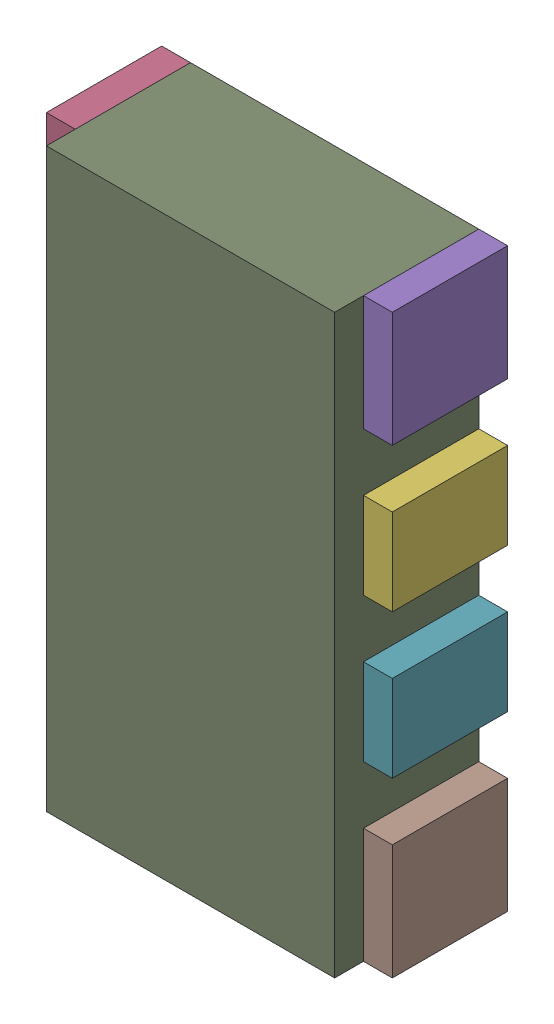
SolidWorks assembly RN9, configuration Default. Lengths in mm.
Overall size (1.2 2 0.5).
18 component instances, 3 part files, 0 mates.
Components (placement in the parent):
- 791587232-1: 791587232 [Default] at (130.6 47.1 0) size (0.1 0.4 0.4)
  - Extruded_10-1: Extruded_10 [Default] at origin size (0.1 0.4 0.4)
- 836750576-1: 836750576 [Default] at (130.6 47.65 0) size (0.1 0.3 0.4)
  - Extruded_14-1: Extruded_14 [Default] at origin size (0.1 0.3 0.4)
- 836750576-2: 836750576 [Default] at (130.6 48.15 0) size (0.1 0.3 0.4)
  - Extruded_14-1: Extruded_14 [Default] at origin size (0.1 0.3 0.4)
- 791587232-2: 791587232 [Default] at (130.6 48.7 0) size (0.1 0.4 0.4)
  - Extruded_10-1: Extruded_10 [Default] at origin size (0.1 0.4 0.4)
- 791587232-3: 791587232 [Default] at (131.7 48.7 0) size (0.1 0.4 0.4)
  - Extruded_10-1: Extruded_10 [Default] at origin size (0.1 0.4 0.4)
- 836750576-3: 836750576 [Default] at (131.7 48.15 0) size (0.1 0.3 0.4)
  - Extruded_14-1: Extruded_14 [Default] at origin size (0.1 0.3 0.4)
- 836750576-4: 836750576 [Default] at (131.7 47.65 0) size (0.1 0.3 0.4)
  - Extruded_14-1: Extruded_14 [Default] at origin size (0.1 0.3 0.4)
- 791587232-4: 791587232 [Default] at (131.7 47.1 0) size (0.1 0.4 0.4)
  - Extruded_10-1: Extruded_10 [Default] at origin size (0.1 0.4 0.4)
- 836750320-1: 836750320 [Default] at (131.15 47.9 0) size (1 2 0.5)
  - Extruded_15-1: Extruded_15 [Default] at origin size (1 2 0.5)
